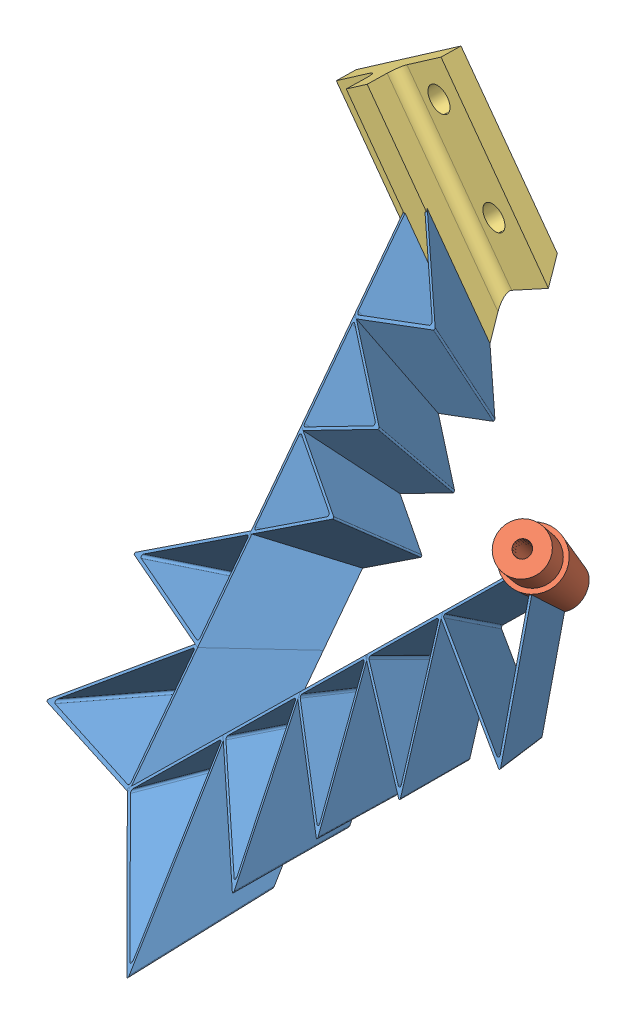
SolidWorks assembly TemplateTetra1, configuration Default. Lengths in mm.
Overall size (166.31 157.41 136.58).
12 component instances, 5 part files, 34 mates.
Components (placement in the parent):
- TemplateTetra1_Tetrahedron-1: TemplateTetra1_Tetrahedron [Default] at (-16.8323 1.1235 19.5825) x (-0.224682 0.85931 -0.459462) z (0.530237 0.503414 0.682219) size (35.88 123.83 41.9)
- TemplateTetra1_Tetrahedron-3: TemplateTetra1_Tetrahedron [Default] at (-13.7595 -5.1071 21.2757) x (-0.413236 0.873509 -0.257328) z (0.544893 0.463603 0.698687) size (35.88 123.83 41.9)
- TemplateTetra1_Tetrahedron-4: TemplateTetra1_Tetrahedron [Default] at (-19.8158 13.1303 10.1485) x (0.018915 -0.779277 0.626395) z (-0.772318 -0.409262 -0.485828) size (35.88 123.83 41.9)
- TemplateTetra1_Tetrahedron-8: TemplateTetra1_Tetrahedron [Default] at (-11.0748 1.5949 23.2995) x (-0.522119 -0.764404 -0.378258) z (-0.764066 0.616288 -0.190768) size (35.88 123.83 41.9)
- TemplateTetra1_Tetrahedron-9: TemplateTetra1_Tetrahedron [Default] at (-6.4434 6.9931 24.0342) x (-0.639018 -0.758563 -0.127434) z (-0.737389 0.651277 -0.17915) size (35.88 123.83 41.9)
- TemplateTetra1_Tetrahedron-10: TemplateTetra1_Tetrahedron [Default] at (8.5897 18.7788 15.5447) x (-0.679304 -0.416024 0.604541) z (-0.641499 0.736713 -0.213853) size (35.88 123.83 41.9)
- TemplateTetra1_Tetrahedron-11: TemplateTetra1_Tetrahedron [Default] at (-1.3619 11.8957 22.9063) x (-0.70696 -0.694606 0.133153) z (-0.706466 0.684663 -0.179281) size (35.88 123.83 41.9)
- TemplateTetra1_Tetrahedron-12: TemplateTetra1_Tetrahedron [Default] at (-18.332 17.5886 4.7585) x (-0.188301 -0.639541 0.745338) z (-0.768427 -0.37667 -0.517338) size (35.88 123.83 41.9)
- TemplateTetra1_Tetrahedron-13: TemplateTetra1_Tetrahedron [Default] at (3.7805 15.9272 20.0023) x (-0.720741 -0.577435 0.383539) z (-0.673665 0.713888 -0.191152) size (35.88 123.83 41.9)
- TemplateTetra1_Tetrahedron-14: TemplateTetra1_Tetrahedron [Default] at (-15.4851 20.669 -1.0326) x (-0.381092 -0.45081 0.80718) z (-0.755348 -0.351623 -0.553002) size (35.88 123.83 41.9)
- TemplateTetra1_EndPart-1: TemplateTetra1_EndPart [Default] at (35.4624 73.321 66.268) x (0.919054 -0.389384 -0.060992) z (-0.203159 -0.600636 0.773281) size (14 115 14)
- TemplateTetra1_Base-1: TemplateTetra1_Base [Default] at (-71.4011 99.7443 -7.0929) x (-0.802702 -0.588169 -0.098628) z (0.079557 0.058294 -0.995124) size (40 92 13)
Mates (geometry in assembly coordinates):
- Coincident14: coincident: point of TemplateTetra1_Tetrahedron-1; point of assembly
- Coincident15: coincident: point of TemplateTetra1_Tetrahedron-1; point of TemplateTetra1_Tetrahedron-3
- Coincident16: coincident: point of TemplateTetra1_Tetrahedron-1; point of TemplateTetra1_Tetrahedron-4
- Coincident17: coincident: line of TemplateTetra1_Tetrahedron-1 through (0 0 0) axis (-0.681227 0.051295 0.730273); line of TemplateTetra1_Tetrahedron-3 through (-20.92 1.5752 22.4262) axis (0.681227 -0.051295 -0.730273)
- Coincident20: coincident: point of TemplateTetra1_Tetrahedron-14; point of TemplateTetra1_Tetrahedron-13
- Coincident21: coincident: point of TemplateTetra1_Tetrahedron-14; point of TemplateTetra1_Tetrahedron-12
- Coincident22: coincident: point of TemplateTetra1_Tetrahedron-14; point of TemplateTetra1_Tetrahedron-9
- Coincident23: coincident: point of TemplateTetra1_Tetrahedron-14; point of TemplateTetra1_Tetrahedron-11
- Coincident24: coincident: point of TemplateTetra1_Tetrahedron-14; point of TemplateTetra1_Tetrahedron-10
- Coincident25: coincident: point of TemplateTetra1_Tetrahedron-14; point of TemplateTetra1_Tetrahedron-8
- Coincident26: coincident: point of TemplateTetra1_Tetrahedron-9; point of assembly
- Coincident27: coincident: line of TemplateTetra1_Tetrahedron-4 through (0 0 0) axis (-0.748652 0.504838 0.42972); line of TemplateTetra1_Tetrahedron-12 through (-22.9906 15.5032 13.1964) axis (0.748652 -0.504838 -0.42972)
- Coincident28: coincident: line of TemplateTetra1_Tetrahedron-12 through (0 0 0) axis (-0.696532 0.681856 0.223419); line of TemplateTetra1_Tetrahedron-14 through (-21.39 20.9393 6.861) axis (0.696532 -0.681856 -0.223419)
- Coincident29: coincident: line of TemplateTetra1_Tetrahedron-8 through (57.9786 -1.5469 20.3073) axis (-0.943484 0.025173 -0.33046); line of TemplateTetra1_Tetrahedron-14 through (0 0 0) axis (0.943484 -0.025173 0.33046)
- Coincident30: coincident: line of TemplateTetra1_Tetrahedron-8 through (0 0 0) axis (-0.422331 0.021096 0.906196); line of TemplateTetra1_Tetrahedron-9 through (-12.9695 0.6478 27.8287) axis (0.422331 -0.021096 -0.906196)
- Coincident31: coincident: line of TemplateTetra1_Tetrahedron-9 through (0 0 0) axis (-0.245458 0.231058 0.941468); line of TemplateTetra1_Tetrahedron-11 through (-7.5379 7.0956 28.9119) axis (0.245458 -0.231058 -0.941468)
- Coincident32: coincident: line of TemplateTetra1_Tetrahedron-11 through (0 0 0) axis (-0.04978 0.423317 0.904613); line of TemplateTetra1_Tetrahedron-13 through (-1.5287 12.9998 27.7801) axis (0.04978 -0.423317 -0.904613)
- Coincident33: coincident: line of TemplateTetra1_Tetrahedron-10 through (4.5976 17.908 24.52) axis (-0.149713 -0.583144 -0.798454); line of TemplateTetra1_Tetrahedron-13 through (0 0 0) axis (0.149713 0.583144 0.798454)
- Parallel6: parallel: plane of TemplateTetra1_Tetrahedron-10 through (8.9193 18.4741 15.7055) normal (-0.691367 0.639042 -0.337101); plane of TemplateTetra1_Tetrahedron-13 through (4.1101 15.6225 20.1631) normal (-0.691367 0.639042 -0.337101)
- Parallel7: parallel: plane of TemplateTetra1_Tetrahedron-10 through (8.9193 18.4741 15.7055) normal (-0.691367 0.639042 -0.337101); plane of TemplateTetra1_Tetrahedron-11 through (-1.0322 11.591 23.0671) normal (-0.691367 0.639042 -0.337101)
- Parallel8: parallel: plane of TemplateTetra1_Tetrahedron-10 through (8.9193 18.4741 15.7055) normal (-0.691367 0.639042 -0.337101); plane of TemplateTetra1_Tetrahedron-9 through (-6.1137 6.6884 24.1949) normal (-0.691367 0.639042 -0.337101)
- Parallel9: parallel: plane of TemplateTetra1_Tetrahedron-10 through (8.9193 18.4741 15.7055) normal (-0.691367 0.639042 -0.337101); plane of TemplateTetra1_Tetrahedron-8 through (-10.7452 1.2902 23.4603) normal (-0.691367 0.639042 -0.337101)
- Parallel10: parallel: plane of TemplateTetra1_Tetrahedron-1 through (-17.1458 0.8938 19.3062) normal (0.657434 0.48171 0.579427); plane of TemplateTetra1_Tetrahedron-3 through (-14.073 -5.3367 20.9995) normal (0.657434 0.48171 0.579427)
- Coincident39: coincident: point of TemplateTetra1_Tetrahedron-1; point of TemplateTetra1_Tetrahedron-4
- Coincident40: coincident: plane of TemplateTetra1_Tetrahedron-1 through (-17.1458 0.8938 19.3062) normal (0.657434 0.48171 0.579427); plane of TemplateTetra1_Tetrahedron-4 through (-19.0485 13.6925 10.8247) normal (0.657434 0.48171 0.579427)
- Parallel13: parallel: plane of TemplateTetra1_Tetrahedron-4 through (-19.0485 13.6925 10.8247) normal (0.657434 0.48171 0.579427); plane of TemplateTetra1_Tetrahedron-12 through (-17.5647 18.1508 5.4348) normal (0.657434 0.48171 0.579427)
- Parallel15: parallel: plane of TemplateTetra1_Tetrahedron-12 through (-17.5647 18.1508 5.4348) normal (0.657434 0.48171 0.579427); plane of TemplateTetra1_Tetrahedron-14 through (-14.7178 21.2312 -0.3563) normal (0.657434 0.48171 0.579427)
- Coincident44: coincident: line of TemplateTetra1_Tetrahedron-3 through (0 0 0) axis (-0.566848 -0.190483 0.801498); line of TemplateTetra1_Tetrahedron-8 through (-17.4075 -5.8496 24.6135) axis (0.566848 0.190483 -0.801498)
- Angle1: planar angle = 1.22173 rad: plane of TemplateTetra1_Tetrahedron-3 through (-14.073 -5.3367 20.9995) normal (0.657434 0.48171 0.579427); plane of TemplateTetra1_Tetrahedron-8 through (-10.7452 1.2902 23.4603) normal (-0.691367 0.639042 -0.337101)
- Coincident49: coincident: point of TemplateTetra1_Tetrahedron-14
- Coincident51: coincident: point of TemplateTetra1_EndPart-1; point of assembly
- Coincident52: coincident: line of TemplateTetra1_Tetrahedron-10 through (0 0 0) axis (0.337737 0.698295 0.631124); line of TemplateTetra1_EndPart-1 through (0 0 0) axis (0.337737 0.698295 0.631124); line of TemplateTetra1_Tetrahedron-14; line of TemplateTetra1_Tetrahedron-14; line of TemplateTetra1_Base-1
- Parallel16: parallel: line of TemplateTetra1_Tetrahedron-14 through (0 0 0) axis (-0.59105 0.806635 0); plane of TemplateTetra1_Base-1 through (-0.9704 37.2973 -5.1203) normal (0.079557 0.058294 -0.995124)
- Parallel17: parallel: line of TemplateTetra1_Tetrahedron-14 through (0 0 0) axis (-0.59105 0.806635 0); line of TemplateTetra1_Base-1 through (-29.4472 76.1609 -5.1203) axis (-0.59105 0.806635 0)
